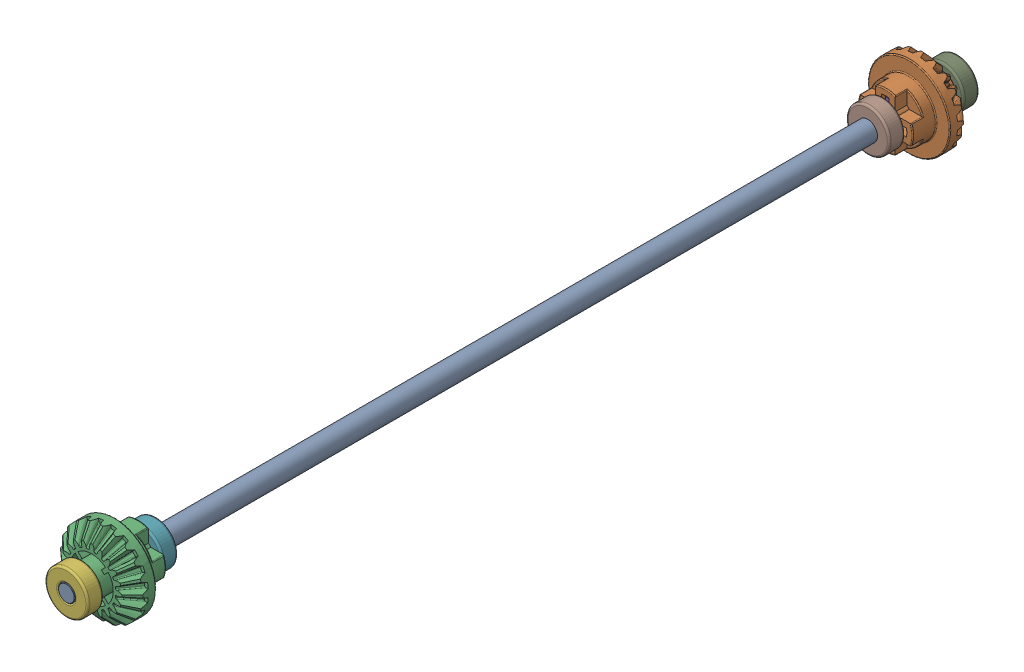
SolidWorks assembly Arbre-transmission, configuration Défaut. Lengths in mm.
Overall size (21 21 228).
9 component instances, 4 part files, 18 mates.
Components (placement in the parent):
- Arbre de transmission-1: Arbre de transmission [Défaut] at origin size (5 5 228)
- Roue-dentée-4-1: Roue-dentée-4 [Configuration] at (0 0 10.5) x (-1 0 0) z (0 0 -1) size (21 21 14.52)
- Roue-dentée-4-2: Roue-dentée-4 [Configuration] at (0 0 217.5) size (21 21 14.52)
- Axe-2-10-1: Axe-2-10 [Défaut] at (0 -5 211) x (1 0 0) z (0 1 0) size (2 2 10)
- Axe-2-10-2: Axe-2-10 [Défaut] at (0 -5 17) x (1 0 0) z (0 1 0) size (2 2 10)
- Coussinet-1: Coussinet [Défaut] at (0 0 224) x (0.957915 0.287052 0) z (0 0 1) size (11 11 4)
- Coussinet-2: Coussinet [Défaut] at (0 0 205) size (11 11 4)
- Coussinet-3: Coussinet [Défaut] at (0 0 19) size (11 11 4)
- Coussinet-4: Coussinet [Défaut] x (0.86912 -0.494602 0) z (0 0 1) size (11 11 4)
Mates (geometry in assembly coordinates):
- Coïncidente1: coincident aligned: axis of Arbre de transmission-1 through (0 0 227.5) axis (0 0 -1); axis of Roue-dentée-4-1 through (0 0 10.5) axis (0 0 -1)
- Coïncidente2: coincident anti-aligned: axis of Arbre de transmission-1 through (0 0 227.5) axis (0 0 -1); axis of Roue-dentée-4-2 through (0 0 217.5) axis (0 0 1)
- Coïncidente4: coincident anti-aligned: axis of Arbre de transmission-1 through (0 -2.5 211) axis (0 1 0); axis of Axe-2-10-1 through (0 4.75 211) axis (0 -1 0)
- A distance1: distance = 5 mm: axis of Arbre de transmission-1 through (0 0 227.5) axis (0 0 -1); plane of Axe-2-10-1 through (0 -5 211) normal (0 -1 0)
- Coïncidente5: coincident anti-aligned: axis of Arbre de transmission-1 through (0 -2.5 17) axis (0 1 0); axis of Axe-2-10-2 through (0 4.75 17) axis (0 -1 0)
- A distance2: distance = 5 mm: axis of Arbre de transmission-1 through (0 0 227.5) axis (0 0 -1); plane of Axe-2-10-2 through (0 -5 17) normal (0 -1 0)
- Parallèle1: parallel aligned: line of Roue-dentée-4-2 through (1 -2.2913 209.5) axis (0 -1 0); axis of Axe-2-10-1 through (0 4.75 211) axis (0 -1 0)
- A distance3: distance = 4 mm aligned: plane of Arbre de transmission-1 through (0 0 228) normal (0 0 1); plane of Roue-dentée-4-2 through (0 0 224) normal (0 0 1)
- Parallèle2: parallel anti-aligned: line of Roue-dentée-4-1 through (1 -5.4083 18.5) axis (0 1 0); axis of Axe-2-10-2 through (0 4.75 17) axis (0 -1 0)
- A distance4: distance = 4 mm aligned: plane of Arbre de transmission-1; plane of Roue-dentée-4-1 through (0 0 4) normal (0 0 -1)
- Coïncidente6: coincident aligned: axis of Arbre de transmission-1 through (0 0 227.5) axis (0 0 -1); axis of Coussinet-1 through (0 0 227.5) axis (0 0 -1)
- Coïncidente7: coincident aligned: axis of Arbre de transmission-1 through (0 0 227.5) axis (0 0 -1); axis of Coussinet-2 through (0 0 208.5) axis (0 0 -1)
- A distance5: distance = 0.5 mm anti-aligned: plane of Roue-dentée-4-2 through (0 0 209.5) normal (0 0 -1); plane of Coussinet-2 through (0 0 209) normal (0 0 1)
- Coïncidente8: coincident anti-aligned: plane of Roue-dentée-4-2 through (0 0 224) normal (0 0 1); plane of Coussinet-1 through (0 0 224) normal (0 0 -1)
- Coïncidente9: coincident aligned: axis of Arbre de transmission-1 through (0 0 227.5) axis (0 0 -1); axis of Coussinet-4 through (0 0 3.5) axis (0 0 -1)
- Coïncidente10: coincident aligned: axis of Arbre de transmission-1 through (0 0 227.5) axis (0 0 -1); axis of Coussinet-3 through (0 0 22.5) axis (0 0 -1)
- A distance6: distance = 0.5 mm anti-aligned: plane of Roue-dentée-4-1 through (0 0 18.5) normal (0 0 1); plane of Coussinet-3 through (0 0 19) normal (0 0 -1)
- Coïncidente11: coincident anti-aligned: plane of Roue-dentée-4-1 through (0 0 4) normal (0 0 -1); plane of Coussinet-4 through (0 0 4) normal (0 0 1)
